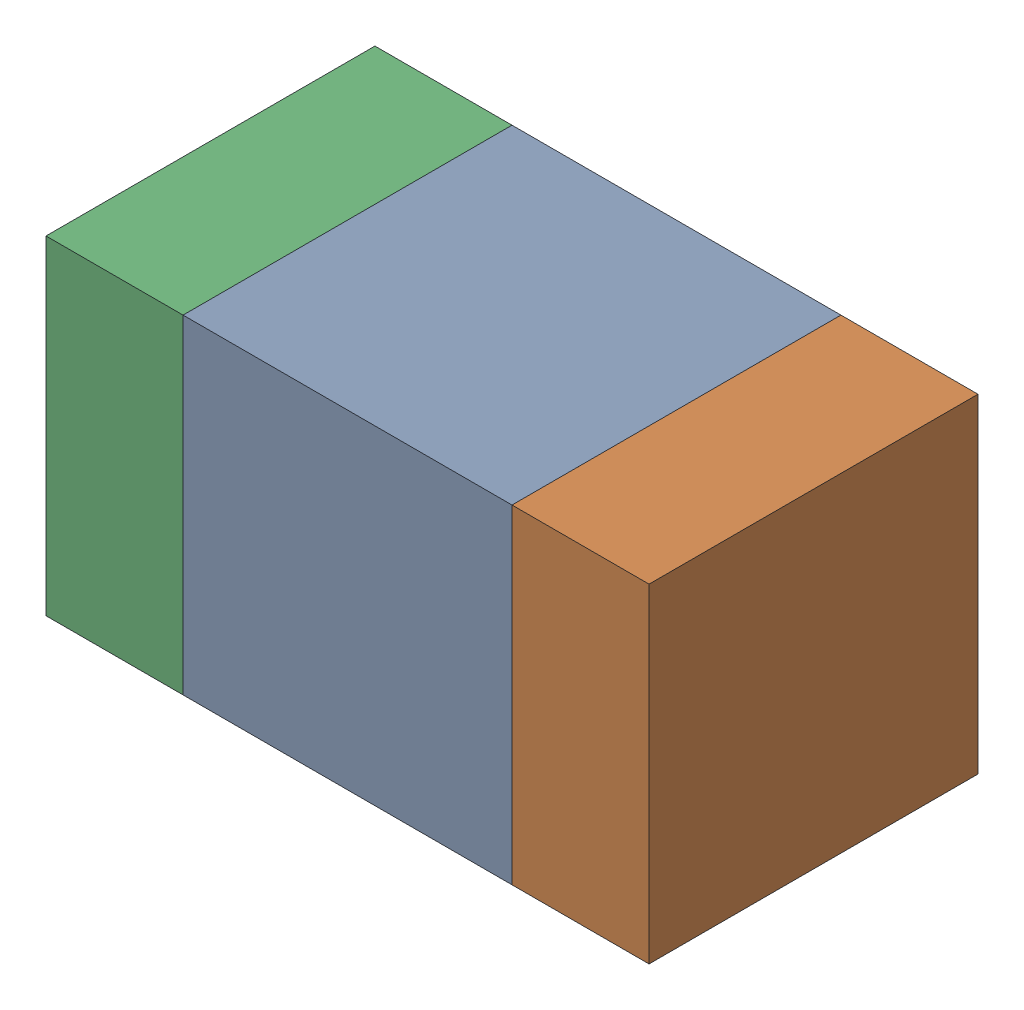
SolidWorks assembly C315_2PCB, configuration Default. Lengths in mm.
Overall size (1.1 0.6 0.6).
6 component instances, 2 part files, 0 mates.
Components (placement in the parent):
- 761606048-1: 761606048 [Default] at (128.1 98 -2.2638) size (0.6 0.6 0.6)
  - Extruded_9-1: Extruded_9 [Default] at origin size (0.6 0.6 0.6)
- 854785160-1: 854785160 [Default] at (128.525 98 -2.2638) size (0.25 0.6 0.6)
  - Extruded_19-1: Extruded_19 [Default] at origin size (0.25 0.6 0.6)
- 854785160-2: 854785160 [Default] at (127.675 98 -2.2638) size (0.25 0.6 0.6)
  - Extruded_19-1: Extruded_19 [Default] at origin size (0.25 0.6 0.6)
